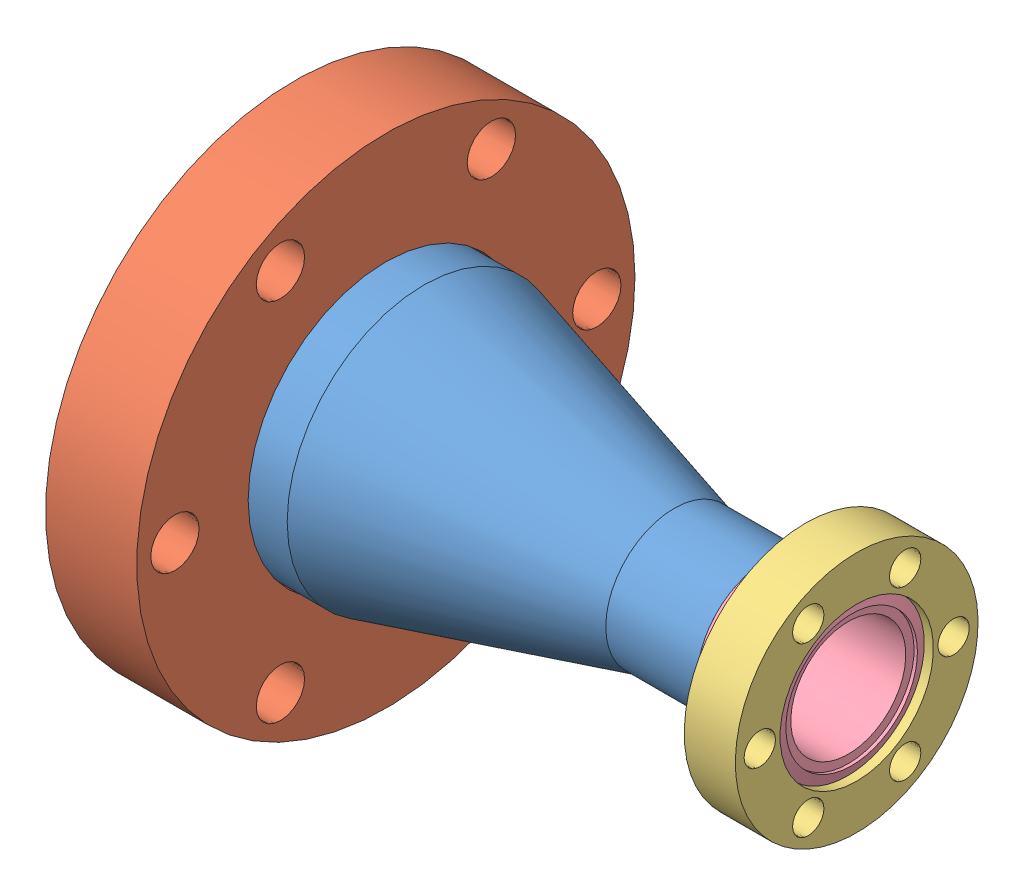
SolidWorks assembly 402030, configuration Default. Lengths in mm.
Overall size (78.23 69.34 69.34).
5 component instances, 4 part files, 0 mates.
Components (placement in the parent):
- 402030-001-1: 402030-001 [Default] at origin size (60.22 38.1 38.1)
- 110014 (2.75 X 1.5 NR)-1: 110014 (2.75 X 1.5 NR) [Default] at (1.0414 0 0) x (-1 0 0) z (0 0 -1) size (12.7 69.34 69.34)
- 100004 (1.33 X .75 R)-1: 100004 (1.33 X .75 R) [Default] at (72.9234 0 0) x (-1 0 0) z (0 0 -1) size (14.22 33.78 33.78)
  - 100004 (1.33 X .75 REC)-1: 100004 (1.33 X .75 REC) [Default] at origin size (7.11 33.78 33.78)
  - 100004 (1.33 X .75 INS)-1: 100004 (1.33 X .75 INS) [Default] at (1.17 0 0) x (1 0 0) z (0 0.470241 -0.882538) size (13.52 21.3 21.3)
